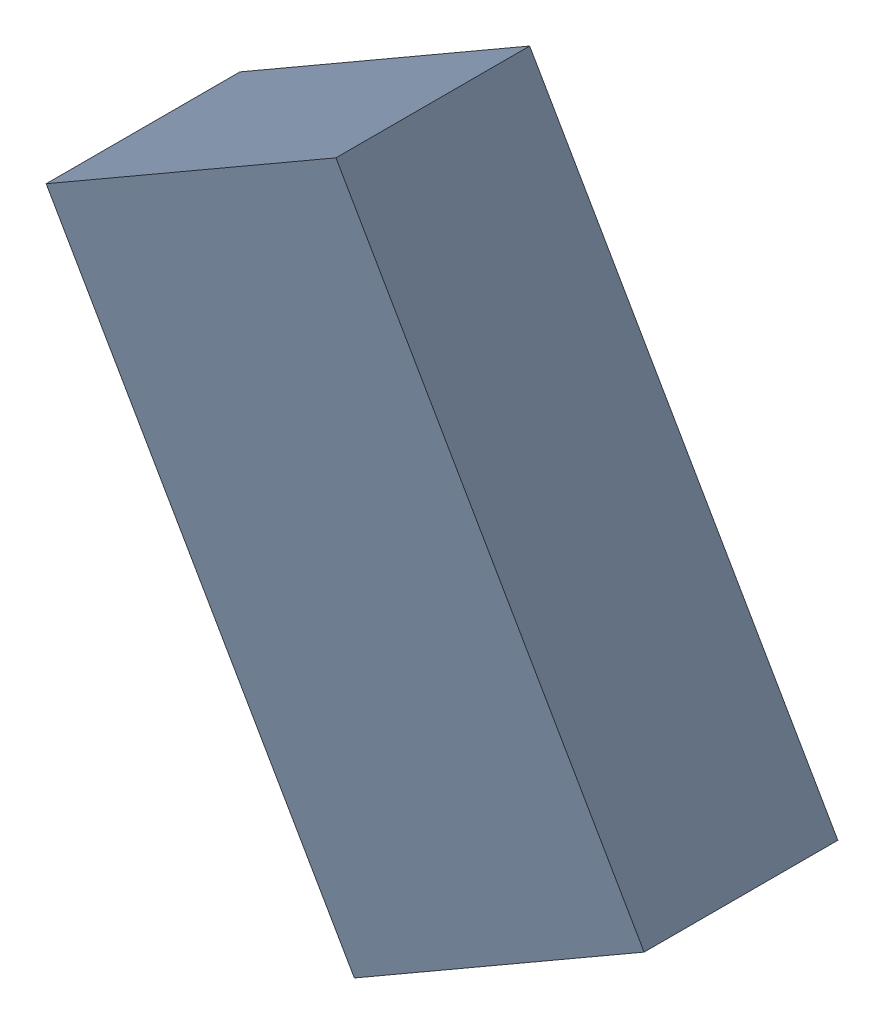
SolidWorks assembly L4_TDA5, configuration Standard. Lengths in mm.
Overall size (1.7 1.99 0.55).
2 component instances, 1 part files, 0 mates.
Components (placement in the parent):
- 885543464-1: 885543464 [Standard] at (-49.7998 -31.9201 0) size (1.7 1.99 0.55)
  - Extruded_18-1: Extruded_18 [Standard] at origin size (1.7 1.99 0.55)
